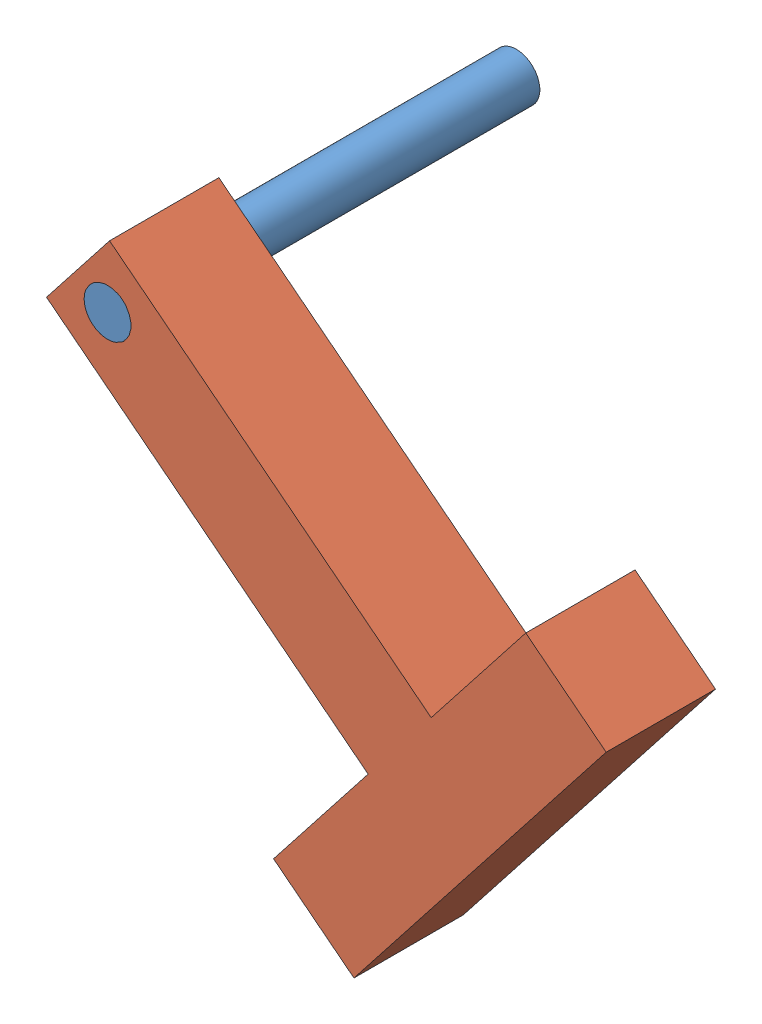
SolidWorks assembly best, configuration Default. Lengths in mm.
Overall size (162.63 158.32 101.6).
2 component instances, 2 part files, 2 mates.
Components (placement in the parent):
- Part2-1: Part2 [Default] at origin size (11.68 11.68 101.6)
- Part1-1: Part1 [Default] at (61.238 -112.7002 75.692) x (0.617033 0.786937 0) z (0 0 1) size (101.6 127 27.18)
Mates (geometry in assembly coordinates):
- Concentric1: concentric aligned: circle of Part2-1; cylinder of Part1-1 through (0 0 62.23) axis (0 0 1) radius 5.8038
- Coincident1: coincident aligned: plane of Part2-1; plane of Part1-1 through (61.238 -112.7002 101.6) normal (0 0 1)
